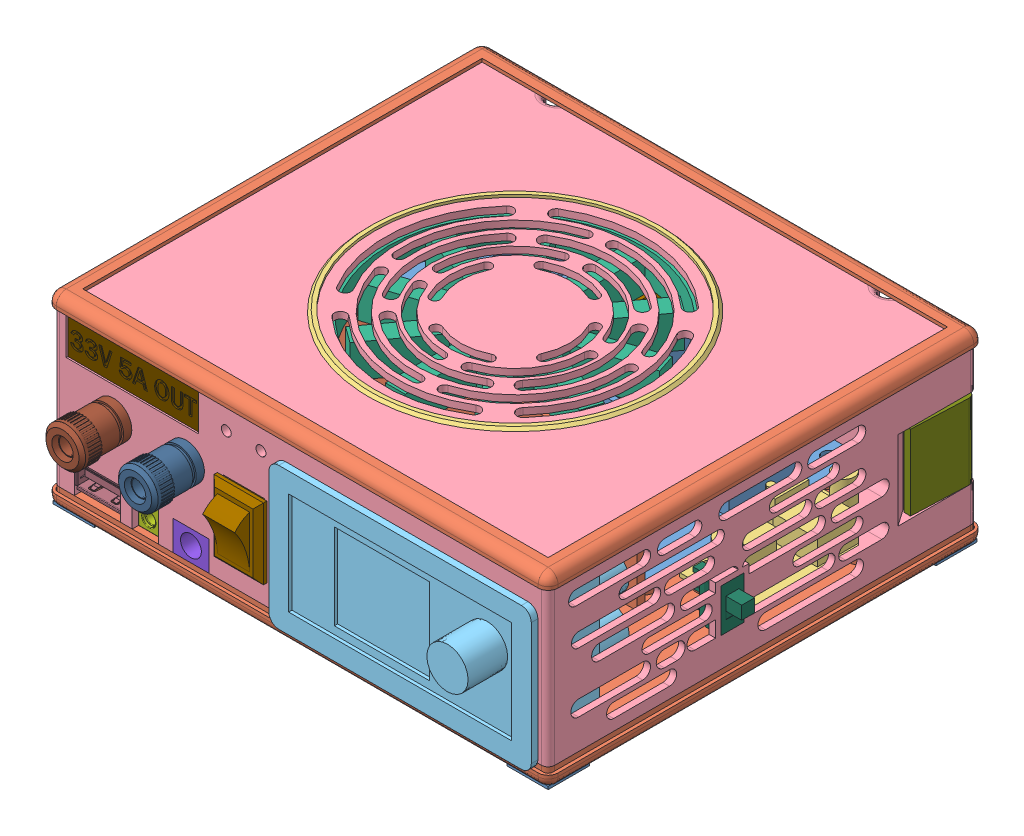
SolidWorks assembly Full Power supply assembly, configuration Default. Lengths in mm.
Overall size (155.77 58.9 152.52).
28 component instances, 21 part files, 76 mates.
Components (placement in the parent):
- 110 and 220 to 36v 5A converter-1: 110 and 220 to 36v 5A converter [Default] at (17.5053 50.1012 82.194) size (115 35.75 66)
- Power supply Base-1: Power supply Base [Default] at (31.2651 43.6012 104.6941) size (150 41.75 130)
- LM2596 DC step down converter-1: LM2596 DC step down converter [Default] at (103.8504 50.1012 75.4301) x (0 0 -1) z (1 0 0) size (43.7 13.7 21)
- Power supply lid-1: Power supply lid [Default] at (43.3739 96.1012 114.2808) x (-1 0 0) z (0 0 1) size (150 50 131.5)
- Step down converter constant current module-1: Step down converter constant current module [Default] at (49.2077 47.6988 182.3498) x (1 0 0) z (0 1 0) size (79.5 47.2 43)
- 80x10mm fan-1: 80x10mm fan [Default] at (30.7634 84.1012 114.8645) size (80 10 80)
- XT60 male-1: XT60 male [Default] at (-4.8675 53.9012 163.5498) x (0 -1 0) z (0 0 1) size (15.6 8 21.8)
- DC Jack-1: DC Jack [Default] at (9.0865 51.253 180.3498) x (0 -1 0) z (1 0 0) size (9 15 15)
- 10A rocker switch-1: 10A rocker switch [Default] at (26.658 62.8742 50.3498) x (1 0 0) z (0 1 0) size (15 25.02 21.5)
- Banana connector female Black-1: Banana connector female Black [Default] at (7.5026 72.1012 195.8498) x (0.923728 0.383049 0) z (-0.383049 0.923728 0) size (12 32.5 20.37)
- Banana connector female RED-1: Banana connector female RED [Default] at (-14.4974 72.1012 195.8498) x (0.923728 0.383049 0) z (-0.383049 0.923728 0) size (12 32.5 20.37)
- XT60 female-1: XT60 female [Default] at (-16.4675 53.9012 136.0069) x (0 -1 0) z (-1 0 0) size (15.6 8 21.4)
- DC Jack-2: DC Jack [Default] at (-32.8675 73.253 136.1726) x (0 -1 0) z (0 0 1) size (9 15 15)
- USB type-A female chassis-1: USB type-A female chassis [Default] at (-94.4886 55.1012 176.572) x (1 0 0) z (0 1 0) size (14.85 14.31 9.58)
- 10A rocker switch-2: 10A rocker switch [Default] at (25.807 57.8742 180.3498) x (-1 0 0) z (0 1 0) size (15 25.02 21.5)
- Screw terminal-1: Screw terminal [Default] at (-19.8675 51.4718 155.7583) x (0 0 1) z (0 -1 0) size (16.65 13 12)
- Switch-1: Switch [Default] at (110.6325 61.9292 126.548) x (0 -1 0) z (0 0 1) size (13 15.27 7)
- Cable clamp-1: Cable clamp [Default] at (102.0026 79.6512 49.5265) x (0.041829 0 -0.999125) z (-0.999125 0 -0.041829) size (22.2 23 27.5)
- Cable clamp-2: Cable clamp [Default] at (-17.6709 56.6512 49.2725) x (-0.014641 0 -0.999893) z (0.999893 0 -0.014641) size (22.2 23 27.5)
- Inscription side-1: Inscription side [Default] at (-31.8675 83.2942 164.1277) x (0 0 1) z (0 -1 0) size (32 1 11.5)
- front inscription-1: front inscription [Default] at (-14.8416 81.046 179.3498) x (1 0 0) z (0 -1 0) size (39.5 1 11.5)
- Rubber feet-1: Rubber feet [Default] at (105.3476 41.6012 57.818) x (-1 0 0) z (0 0 1) size (12.5 3.4 12.5)
- Rubber feet-2: Rubber feet [Default] at (105.3476 41.6012 175.318) x (-1 0 0) z (0 0 1) size (12.5 3.4 12.5)
- Rubber feet-3: Rubber feet [Default] at (-32.1524 41.6012 57.818) x (-1 0 0) z (0 0 1) size (12.5 3.4 12.5)
- Rubber feet-4: Rubber feet [Default] at (-32.1524 41.6012 175.318) x (-1 0 0) z (0 0 1) size (12.5 3.4 12.5)
- side skirts-1: side skirts [Default] at (42.5119 93.1012 107.3831) x (1 0 0) z (0 1 0) size (152 132 4)
- side skirts-2: side skirts [Default] at (42.5119 44.6012 123.3165) x (1 0 0) z (0 -1 0) size (152 132 4)
- Fan ring-1: Fan ring [Default] at (42.1325 96.1012 115.3498) size (89 0.8 89)
Mates (geometry in assembly coordinates):
- Distance1: distance = 4 mm: plane of Power supply Base-1 through (31.2651 46.1012 104.6941) normal (0 1 0); plane of 110 and 220 to 36v 5A converter-1 through (17.5053 50.1012 82.194) normal (0 -1 0)
- Distance2: distance = 6 mm: plane of 110 and 220 to 36v 5A converter-1 through (-26.8675 51.8512 56.3498) normal (-1 0 0); plane of Power supply Base-1 through (-32.8675 46.1012 50.3498) normal (-1 0 0)
- Distance3: distance = 6 mm: plane of Power supply Base-1 through (-32.8675 46.1012 50.3498) normal (0 0 -1); plane of 110 and 220 to 36v 5A converter-1 through (-26.8675 51.8512 56.3498) normal (0 0 -1)
- Distance4: distance = 4 mm: plane of Power supply Base-1 through (31.2651 46.1012 104.6941) normal (0 1 0); plane of LM2596 DC step down converter-1 through (103.8504 50.1012 75.4301) normal (0 -1 0)
- Distance6: distance = 20 mm: plane of LM2596 DC step down converter-1 through (111.6325 51.3012 70.3498) normal (0 0 -1); plane of Power supply Base-1 through (-32.8675 46.1012 50.3498) normal (0 0 -1)
- Distance7: distance = 5.5 mm: plane of Power supply Base-1 through (117.1325 46.1012 50.3498) normal (1 0 0); plane of LM2596 DC step down converter-1 through (111.6325 51.3012 70.3498) normal (1 0 0)
- Coincident1: coincident: plane of Power supply Base-1 through (31.2651 46.1012 104.6941) normal (0 1 0); plane of Power supply lid-1 through (43.3739 46.1012 114.2808) normal (0 -1 0)
- Coincident2: coincident: plane of Power supply Base-1 through (-32.8675 46.1012 180.3498) normal (0 0 1); plane of Power supply lid-1 through (117.1325 94.1012 180.3498) normal (0 0 1)
- Coincident3: coincident: plane of Power supply Base-1 through (-32.8675 46.1012 50.3498) normal (-1 0 0); plane of Power supply lid-1 through (-32.8675 94.1012 50.3498) normal (-1 0 0)
- Coincident4: coincident: plane of Power supply lid-1 through (117.1325 94.1012 180.3498) normal (0 0 1); plane of Step down converter constant current module-1 through (49.2077 47.6988 180.3498) normal (0 0 -1)
- Coincident7: coincident: plane of Power supply lid-1 through (117.1325 94.1012 180.3498) normal (0 0 1); plane of Step down converter constant current module-1 through (49.2077 47.6988 180.3498) normal (0 0 -1)
- Distance9: distance = 7 mm: plane of Step down converter constant current module-1 through (110.1325 46.1012 157.7498) normal (1 0 0); plane of Power supply lid-1 through (117.1325 94.1012 50.3498) normal (1 0 0)
- Distance10: distance = 0 mm: plane of Step down converter constant current module-1 through (38.4325 46.1012 157.7498) normal (0 -1 0); plane of Power supply Base-1 through (31.2651 46.1012 104.6941) normal (0 1 0)
- Distance11: distance = 2 mm: plane of 80x10mm fan-1 through (30.7634 94.1012 114.8645) normal (0 1 0); plane of Power supply lid-1 through (43.3739 96.1012 114.2808) normal (0 1 0)
- Distance12: distance = 35 mm: plane of 80x10mm fan-1 through (82.1325 94.1012 75.3498) normal (1 0 0); plane of Power supply lid-1 through (117.1325 94.1012 50.3498) normal (1 0 0)
- Distance13: distance = 25 mm: plane of 80x10mm fan-1 through (2.1325 94.1012 155.3498) normal (0 0 1); plane of Power supply lid-1 through (117.1325 94.1012 180.3498) normal (0 0 1)
- Coincident13: coincident: plane of Power supply lid-1 through (-26.4344 55.1012 178.3498) normal (0 -1 0); plane of USB type-A female chassis-1 through (-19.0094 55.1012 173.0498) normal (0 1 0)
- Coincident14: coincident: plane of Power supply lid-1 through (117.1325 94.1012 180.3498) normal (0 0 1); plane of USB type-A female chassis-1 through (-19.0094 48.7013 180.3498) normal (0 0 1)
- Coincident15: coincident: plane of Power supply lid-1 through (-26.4344 55.1012 178.3498) normal (1 0 0); plane of USB type-A female chassis-1 through (-26.4344 51.9012 180.1871) normal (-1 0 0)
- Coincident17: coincident: plane of Power supply lid-1 through (117.1325 94.1012 180.3498) normal (0 0 1); plane of DC Jack-1 through (9.0865 51.253 180.3498) normal (0 0 1)
- Coincident18: coincident: plane of Power supply Base-1 through (31.2651 46.1012 104.6941) normal (0 1 0); plane of DC Jack-1 through (3.4208 46.1012 165.3498) normal (0 -1 0)
- Coincident19: coincident: plane of Power supply lid-1 through (14.4208 55.1012 178.3498) normal (-1 0 0); plane of DC Jack-1 through (14.4208 55.1012 165.3498) normal (1 0 0)
- Coincident20: coincident: plane of Power supply Base-1 through (31.2651 46.1012 104.6941) normal (0 1 0); plane of XT60 male-1 through (-8.8675 46.1012 163.5498) normal (0 -1 0)
- Coincident21: coincident: plane of Power supply lid-1 through (117.1325 94.1012 180.3498) normal (0 0 1); plane of XT60 male-1 through (-4.8675 53.9012 180.3498) normal (0 0 1)
- Coincident22: coincident: plane of Power supply lid-1 through (-8.8675 62.1012 178.3498) normal (1 0 0); plane of XT60 male-1 through (-8.8675 58.7012 163.5498) normal (-1 0 0)
- Concentric1: concentric: cylinder of Power supply lid-1 through (-14.4974 72.1012 178.3498) axis (0 0 1) radius 4; cylinder of Banana connector female RED-1 through (-14.4974 72.1012 178.3498) axis (0 0 1) radius 3.85
- Coincident23: coincident: plane of Power supply lid-1 through (117.1325 94.1012 180.3498) normal (0 0 1); plane of Banana connector female RED-1 through (-14.4974 72.1012 180.3498) normal (0 0 -1)
- Concentric2: concentric: cylinder of Power supply lid-1 through (7.5026 72.1012 178.3498) axis (0 0 1) radius 4; cylinder of Banana connector female Black-1 through (7.5026 72.1012 178.3498) axis (0 0 1) radius 3.85
- Coincident24: coincident: plane of Power supply lid-1 through (117.1325 94.1012 180.3498) normal (0 0 1); plane of Banana connector female Black-1 through (7.5026 72.1012 180.3498) normal (0 0 -1)
- Coincident25: coincident: plane of Power supply lid-1 through (117.1325 94.1012 180.3498) normal (0 0 1); plane of 10A rocker switch-2 through (25.807 57.8742 180.3498) normal (0 0 -1)
- Coincident26: coincident: plane of Power supply lid-1 through (18.6325 74.1012 178.3498) normal (1 0 0); plane of 10A rocker switch-2 through (18.6325 72.1012 169.3498) normal (-1 0 0)
- Coincident27: coincident: plane of Power supply lid-1 through (18.6325 54.1012 178.3498) normal (0 1 0); plane of 10A rocker switch-2 through (30.3325 54.1012 169.3498) normal (0 -1 0)
- Coincident28: coincident: plane of Power supply Base-1 through (31.2651 46.1012 104.6941) normal (0 1 0); plane of XT60 female-1 through (-16.4675 46.1012 132.0069) normal (0 -1 0)
- Coincident29: coincident: plane of Power supply lid-1 through (-32.8675 94.1012 50.3498) normal (-1 0 0); plane of XT60 female-1 through (-32.8675 53.2562 136.0069) normal (-1 0 0)
- Coincident30: coincident: plane of Power supply lid-1 through (-30.8675 59.7012 132.0069) normal (0 0 1); plane of XT60 female-1 through (-16.4675 58.7012 132.0069) normal (0 0 -1)
- Coincident31: coincident: plane of Power supply lid-1 through (-32.8675 94.1012 50.3498) normal (-1 0 0); plane of DC Jack-2 through (-32.8675 73.253 136.1726) normal (-1 0 0)
- Coincident32: coincident: plane of Power supply lid-1 through (-30.8675 68.1012 130.5069) normal (0 1 0); plane of DC Jack-2 through (-17.8675 68.1012 130.5069) normal (0 -1 0)
- Coincident33: coincident: plane of Power supply lid-1 through (-30.8675 77.1012 141.5069) normal (0 0 -1); plane of DC Jack-2 through (-17.8675 77.1012 141.5069) normal (0 0 1)
- Coincident34: coincident: plane of Power supply lid-1 through (34.6325 59.1012 52.8898) normal (0 1 0); plane of 10A rocker switch-1 through (22.1325 59.1012 61.3498) normal (0 -1 0)
- Coincident35: coincident: plane of Power supply lid-1 through (22.1325 79.1012 52.8898) normal (1 0 0); plane of 10A rocker switch-1 through (22.1325 77.1012 61.3498) normal (-1 0 0)
- Coincident36: coincident: plane of Power supply lid-1 through (117.1325 94.1012 50.3498) normal (0 0 -1); plane of 10A rocker switch-1 through (26.658 62.8742 50.3498) normal (0 0 1)
- Coincident37: coincident: plane of Power supply Base-1 through (31.2651 46.1012 104.6941) normal (0 1 0); plane of Screw terminal-1 through (-32.8675 46.1012 146.9743) normal (0 -1 0)
- Coincident38: coincident: plane of Power supply lid-1 through (-30.8675 68.1012 146.9743) normal (0 0 1); plane of Screw terminal-1 through (-32.8675 58.1012 146.9743) normal (0 0 -1)
- Coincident39: coincident: plane of Power supply lid-1 through (-32.8675 94.1012 50.3498) normal (-1 0 0); plane of Screw terminal-1 through (-32.8675 51.4718 155.7583) normal (-1 0 0)
- Coincident43: coincident: plane of Power supply lid-1 through (95.1325 67.9536 128.022) normal (0 0 -1); plane of Switch-1 through (110.6325 61.9292 128.022) normal (0 0 1)
- Coincident44: coincident: plane of Power supply lid-1 through (95.1325 54.9536 128.022) normal (0 1 0); plane of Switch-1 through (117.0325 54.9536 121.122) normal (0 -1 0)
- Coincident45: coincident: plane of Power supply lid-1 through (117.1325 94.1012 50.3498) normal (1 0 0); plane of Switch-1 through (117.1325 61.9292 126.548) normal (1 0 0)
- Concentric3: concentric: circle of Power supply lid-1; cylinder of Cable clamp-2 through (-8.3675 79.6512 51.8498) axis (0 -1 0) radius 1.4
- Coincident46: coincident: plane of Power supply lid-1 through (-8.3675 60.8512 51.8498) normal (0 1 0); plane of Cable clamp-2 through (-8.3675 60.8512 51.8498) normal (0 -1 0)
- Concentric4: concentric: cylinder of Power supply lid-1 through (92.6325 96.1012 51.8498) axis (0 -1 0) radius 1.6; cylinder of Cable clamp-1 through (92.6325 56.6512 51.8498) axis (0 1 0) radius 1.4
- Coincident47: coincident: plane of Power supply lid-1 through (92.6325 60.8512 51.8498) normal (0 1 0); plane of Cable clamp-1 through (92.6325 60.8512 51.8498) normal (0 -1 0)
- Coincident48: coincident: plane of Power supply lid-1 through (43.3739 96.1012 179.3498) normal (0 0 1); plane of front inscription-1 through (-14.8416 81.046 179.3498) normal (0 0 -1)
- Coincident49: coincident: plane of Power supply lid-1 through (11.1325 93.1012 179.3498) normal (0 -1 0); plane of front inscription-1 through (-28.3675 93.1012 180.3498) normal (0 1 0)
- Coincident50: coincident: plane of Power supply lid-1 through (11.1325 81.1012 179.3498) normal (-1 0 0); plane of front inscription-1 through (11.1325 93.1012 180.3498) normal (1 0 0)
- Coincident51: coincident: plane of Power supply lid-1 through (-31.8675 96.1012 114.2808) normal (-1 0 0); plane of Inscription side-1 through (-31.8675 83.2942 164.1277) normal (1 0 0)
- Coincident52: coincident: plane of Power supply lid-1 through (-31.8675 81.1012 176.3498) normal (0 1 0); plane of Inscription side-1 through (-32.8675 81.1012 144.3498) normal (0 -1 0)
- Coincident53: coincident: plane of Power supply lid-1 through (-31.8675 81.1012 144.3498) normal (0 0 1); plane of Inscription side-1 through (-32.8675 92.6012 144.3498) normal (0 0 -1)
- Coincident54: coincident: plane of Power supply Base-1 through (31.2651 41.6012 104.6941) normal (0 -1 0); plane of Rubber feet-4 through (-32.1524 41.6012 175.318) normal (0 1 0)
- Coincident55: coincident: plane of Power supply Base-1 through (-32.8675 46.1012 50.3498) normal (-1 0 0); plane of Rubber feet-4 through (-32.8675 38.2012 180.3498) normal (-1 0 0)
- Coincident56: coincident: plane of Power supply Base-1 through (-32.8675 46.1012 180.3498) normal (0 0 1); plane of Rubber feet-4 through (-32.8675 38.2012 180.3498) normal (0 0 1)
- Coincident57: coincident: plane of Power supply Base-1 through (31.2651 41.6012 104.6941) normal (0 -1 0); plane of Rubber feet-2 through (105.3476 41.6012 175.318) normal (0 1 0)
- Coincident58: coincident: plane of Power supply Base-1 through (117.1325 46.1012 50.3498) normal (1 0 0); plane of Rubber feet-2 through (117.1325 38.2012 180.3498) normal (1 0 0)
- Coincident59: coincident: plane of Power supply Base-1 through (-32.8675 46.1012 180.3498) normal (0 0 1); plane of Rubber feet-2 through (104.6325 38.2012 180.3498) normal (0 0 1)
- Coincident60: coincident: plane of Power supply Base-1 through (31.2651 41.6012 104.6941) normal (0 -1 0); plane of Rubber feet-1 through (105.3476 41.6012 57.818) normal (0 1 0)
- Coincident61: coincident: plane of Power supply Base-1 through (117.1325 46.1012 50.3498) normal (1 0 0); plane of Rubber feet-1 through (117.1325 38.2012 62.8498) normal (1 0 0)
- Coincident62: coincident: plane of Power supply Base-1 through (-32.8675 46.1012 50.3498) normal (0 0 -1); plane of Rubber feet-1 through (104.6325 38.2012 50.3498) normal (0 0 -1)
- Coincident63: coincident: plane of Power supply Base-1 through (31.2651 41.6012 104.6941) normal (0 -1 0); plane of Rubber feet-3 through (-32.1524 41.6012 57.818) normal (0 1 0)
- Coincident64: coincident: plane of Power supply Base-1 through (-32.8675 46.1012 50.3498) normal (0 0 -1); plane of Rubber feet-3 through (-32.8675 38.2012 50.3498) normal (0 0 -1)
- Coincident65: coincident: plane of Power supply Base-1 through (-32.8675 46.1012 50.3498) normal (-1 0 0); plane of Rubber feet-3 through (-32.8675 38.2012 62.8498) normal (-1 0 0)
- Coincident66: coincident: plane of assembly; plane of assembly; plane of Power supply lid-1 through (43.3739 96.1012 114.2808) normal (0 1 0); plane of side skirts-1 through (42.5119 96.1012 107.3831) normal (0 -1 0)
- Coincident67: coincident: plane of assembly; plane of assembly; plane of Power supply lid-1 through (117.1325 94.1012 180.3498) normal (0 0 1); plane of side skirts-1 through (-32.8675 96.1012 180.3498) normal (0 0 -1)
- Coincident68: coincident: plane of assembly; plane of assembly; plane of Power supply lid-1 through (-32.8675 94.1012 50.3498) normal (-1 0 0); plane of side skirts-1 through (-32.8675 96.1012 50.3498) normal (1 0 0)
- Coincident69: coincident: plane of assembly; plane of assembly; plane of Power supply Base-1 through (31.2651 41.6012 104.6941) normal (0 -1 0); plane of side skirts-2 through (42.5119 41.6012 123.3165) normal (0 1 0)
- Coincident70: coincident: plane of assembly; plane of assembly; plane of Power supply Base-1 through (117.1325 46.1012 50.3498) normal (1 0 0); plane of side skirts-2 through (117.1325 41.6012 180.3498) normal (-1 0 0)
- Coincident71: coincident: plane of assembly; plane of assembly; plane of Power supply Base-1 through (-32.8675 46.1012 180.3498) normal (0 0 1); plane of side skirts-2 through (-32.8675 41.6012 180.3498) normal (0 0 -1)
- Concentric5: concentric: cylinder of assembly; cylinder of assembly; cylinder of Power supply lid-1 through (42.1325 93.5612 115.3498) axis (0 1 0) radius 39.323; cylinder of Fan ring-1 through (42.1325 96.9012 115.3498) axis (0 -1 0) radius 42.5
